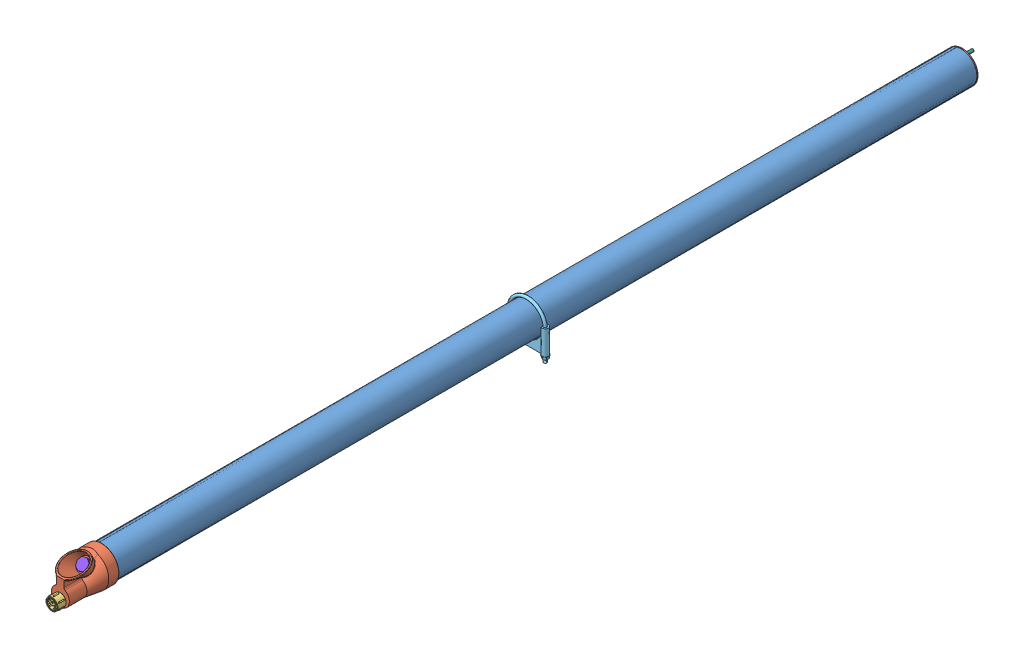
SolidWorks assembly Roof Shower Assembly, configuration Default. Lengths in mm.
Overall size (120.45 136.76 2587.07).
9 component instances, 8 part files, 17 mates.
Components (placement in the parent):
- 3in Pipe-2: 3in Pipe [Default] at origin size (88.9 88.9 2438.4)
- 3in Pipe Cap with Spigot-1: 3in Pipe Cap with Spigot [Default] at (0 0 1219.2) size (98.78 101.9 117.76)
- 4211N223_Standard-Wall Plastic Pipe Fitting for Water-1: 4211N223_Standard-Wall Plastic Pipe Fitting for Water [4211N223] at (0 -29.845 1310.64) x (0 0 -1) z (1 0 0) size (40.99 36.57 33.53)
- 3in Cap-1: 3in Cap [Default] at (0 0 -1219.2) x (-1 0 0) z (0 0 -1) size (88.9 88.9 16.51)
- 3042T37_Clamping U-Bolt-1: 3042T37_Clamping U-Bolt [3042T37] at (0 -2.2058 -0.7136) x (-1 0 0) z (0 0 1) size (120.45 136.76 18.85)
- CKAuto TR416 Metal Valve Stem-2: CKAuto TR416 Metal Valve Stem [Default] at (0 24.5999 -1212.1896) x (1 0 0) z (0 1 0) size (18.52 40.06 18.52)
  - CKAuto TR416 Metal Valve Base-2: CKAuto TR416 Metal Valve Base [Default] at origin size (18.52 40.06 18.52)
  - Part12^CKAuto TR416 Metal Valve Stem-1: Part12^CKAuto TR416 Metal Valve Stem [Default] x (0 0 -1) z (1 0 0) size (17.78 7.25 17.78) (virtual)
- 4880K542_Standard-Wall PVC Pipe Fitting for Water-1: 4880K542_Standard-Wall PVC Pipe Fitting for Water [4880K542] at (0 16.6115 1238.9262) x (-0.855307 0.396317 -0.333741) z (0 -0.644136 -0.764911) size (29.77 29.77 27)
Mates (geometry in assembly coordinates):
- Coincident1: coordinate: point of 3in Pipe-2
- InPlace1: in place: plane of 3in Pipe-2 through (0 0 1219.2) normal (0 0 1); plane of 3in Pipe Cap with Spigot-1 through (0 0 1219.2) normal (0 0 1); moOrthogonalPlaneRef_w of 3in Pipe-2 through (0 0 1219.2) normal (0 0 1); plane of 3in Pipe Cap with Spigot-1 through (0 0 1219.2) normal (0 1 0); plane of 3in Pipe-2 through (0 0 1219.2) normal (0 0 1); plane of 3in Pipe Cap with Spigot-1 through (0 0 1219.2) normal (1 0 0); plane of 3in Pipe-2 through (0 0 1219.2) normal (0 0 1); unknown of 3in Pipe Cap with Spigot-1
- Coincident2: coincident: plane of 3in Pipe-2; plane of 3in Pipe Cap with Spigot-1
- Coincident3: coincident aligned: moOrthogonalPlaneRef_w of 3in Pipe-2 through (0 0 1219.2) normal (0 1 0); plane of 3in Pipe Cap with Spigot-1 through (0 0 1219.2) normal (0 1 0)
- Coincident4: coincident anti-aligned: moOrthogonalPlaneRef_w of 3in Pipe-2 through (0 0 1219.2) normal (-1 0 0); plane of 3in Pipe Cap with Spigot-1 through (0 0 1219.2) normal (1 0 0)
- Coincident6: coincident aligned: plane of 4211N223_Standard-Wall Plastic Pipe Fitting for Water-1 through (0 -29.845 1310.64) normal (1 0 0)
- InPlace2: in place: plane of 3in Pipe-2 through (0 0 -1219.2) normal (0 0 -1); plane of 3in Cap-1 through (0 0 -1219.2) normal (0 0 -1); plane of 3in Pipe-2 through (0 0 -1219.2) normal (0 0 -1); plane of 3in Cap-1 through (0 0 -1219.2) normal (0 1 0); plane of 3in Pipe-2 through (0 0 -1219.2) normal (0 0 -1); plane of 3in Cap-1 through (0 0 -1219.2) normal (-1 0 0); plane of 3in Pipe-2 through (0 0 -1219.2) normal (0 0 -1); unknown of 3in Cap-1
- Coincident9: coincident aligned: plane of 3in Pipe-2; plane of 3in Cap-1
- Coincident10: coincident aligned: moOrthogonalPlaneRef_w of 3in Pipe-2 through (0 0 -1219.2) normal (0 1 0); plane of 3in Cap-1 through (0 0 -1219.2) normal (0 1 0)
- Coincident11: coincident anti-aligned: moOrthogonalPlaneRef_w of 3in Pipe-2 through (0 0 -1219.2) normal (1 0 0); plane of 3in Cap-1 through (0 0 -1219.2) normal (-1 0 0)
- Concentric2: concentric anti-aligned: cylinder of 3in Pipe-2 through (0 0 1219.2) axis (0 0 -1) radius 44.45; cylinder of 3042T37_Clamping U-Bolt-1 through (0 0 -10.137) axis (0 0 1) radius 46.8781
- Parallel1: parallel anti-aligned: plane of 3042T37_Clamping U-Bolt-1 through (-50.8 -64.3406 -0.7136) normal (0 -1 0)
- Coincident28: coincident anti-aligned: plane of 3in Cap-1 through (0 0 -1219.2) normal (-1 0 0); plane of CKAuto TR416 Metal Valve Stem-2 through (0 24.5999 -1212.1896) normal (1 0 0)
- Coincident29: coincident anti-aligned: plane of 3in Cap-1 through (0 0 -1219.2) normal (0 0 1); plane of CKAuto TR416 Metal Valve Stem-2/Part12^CKAuto TR416 Metal Valve Stem-1 through (0 33.3629 -1219.2) normal (0 0 -1)
- Tangent2: tangent: circle of 3in Cap-1; cone of CKAuto TR416 Metal Valve Stem-2/Part12^CKAuto TR416 Metal Valve Stem-1 through (0 24.5999 -1219.2) axis (0 0 -1)
- Coincident39: coincident anti-aligned: plane of 3in Pipe Cap with Spigot-1 through (0 20.7284 1243.8149) normal (0 0.644136 0.764911); plane of 4880K542_Standard-Wall PVC Pipe Fitting for Water-1 through (0 20.7284 1243.8149) normal (0 -0.644136 -0.764911)
- Coincident40: coincident anti-aligned: plane of 3in Pipe Cap with Spigot-1 through (0.0001 -23.0505 1310.64) normal (0 0 1); plane of 4211N223_Standard-Wall Plastic Pipe Fitting for Water-1 through (0 -29.845 1310.64) normal (0 0 -1)
